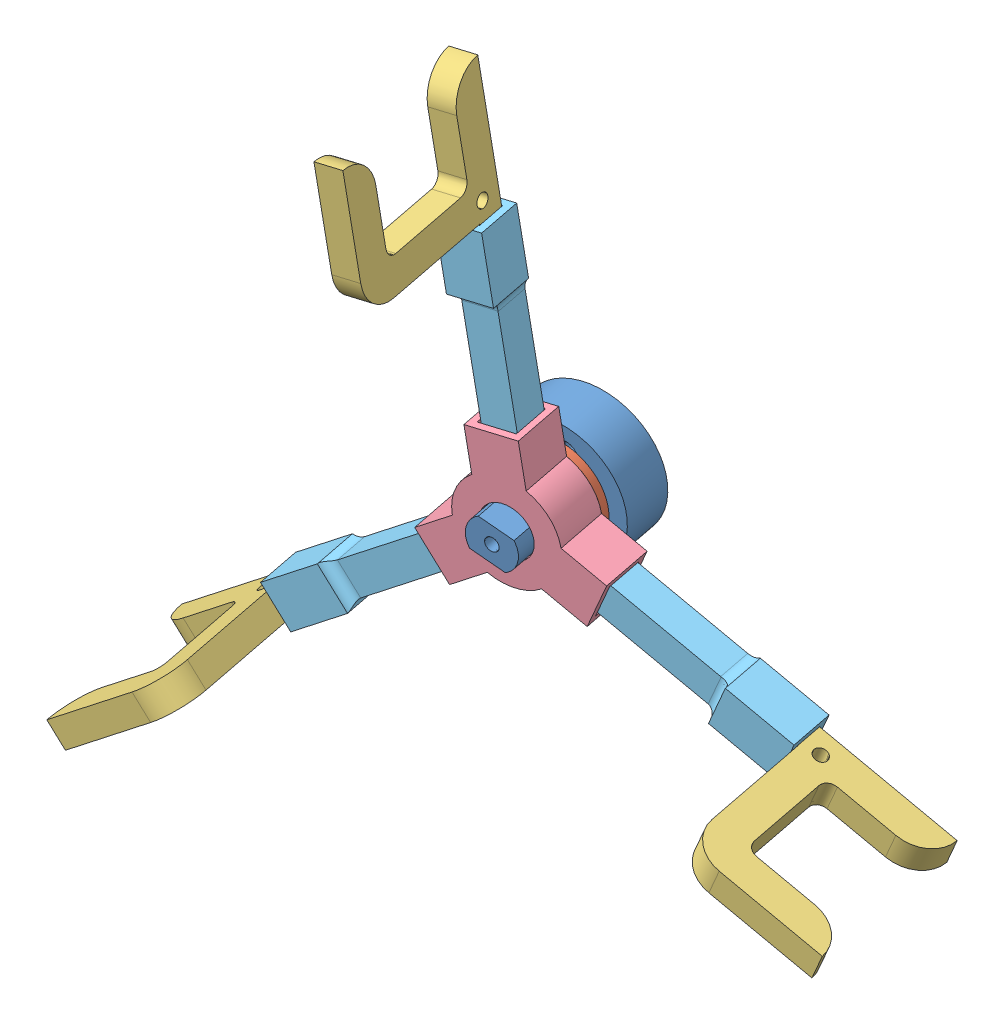
SolidWorks assembly Filament Spool assy, configuration По умолчанию. Lengths in mm.
Overall size (242.81 243.28 106.81).
9 component instances, 5 part files, 25 mates.
Components (placement in the parent):
- spool axes-1: spool axes [По умолчанию] at (2.9579 -0.3616 6.1587) x (0.266619 0.963729 0.011885) z (0.952076 -0.261437 -0.158752) size (40 38 40)
- spool washer 1-1: spool washer 1 [По умолчанию] at (5.5809 -1.3004 23.4355) x (-0.266619 -0.963729 -0.011885) z (0.952076 -0.261437 -0.158752) size (30 2.5 30)
- spool horn-4: spool horn [По умолчанию] at (83.0333 -30.0144 24.6517) x (-0.149887 0.053642 -0.987247) z (-0.392723 -0.919606 0.009658) size (50 60 8)
- spool horn-5: spool horn [По умолчанию] at (-5.4255 77.9644 43.9488) x (-0.149887 0.053642 -0.987247) z (0.982159 0.122779 -0.142443) size (50 60 8)
- spool horn-6: spool horn [По умолчанию] at (-54.4123 -54.1604 44.2071) x (-0.149887 0.053642 -0.987247) z (-0.589436 0.796827 0.132785) size (50 60 8)
- spool hub-2: spool hub [По умолчанию] at (5.5809 -1.3004 23.4355) x (0.982159 0.122779 -0.142443) z (0.149887 -0.053642 0.987247) size (52.98 45.88 15)
- spool needle-4: spool needle [По умолчанию] at (38.7951 -15.5234 19.7472) x (-0.392723 -0.919606 0.009658) z (0.149887 -0.053642 0.987247) size (13.39 70 13.21)
- spool needle-5: spool needle [По умолчанию] at (-22.8857 -23.2341 28.6928) x (-0.589436 0.796827 0.132785) z (0.149887 -0.053642 0.987247) size (13.39 70 13.21)
- spool needle-6: spool needle [По умолчанию] at (1.7778 34.5184 28.0863) x (0.982159 0.122779 -0.142443) z (0.149887 -0.053642 0.987247) size (13.39 70 13.21)
Mates (geometry in assembly coordinates):
- Концентричный2: concentric anti-aligned: cylinder of spool axes-1 through (8.0811 -2.1951 39.9032) axis (-0.149887 0.053642 -0.987247) radius 7.25; cylinder of spool washer 1-1 through (4.6337 -0.9614 17.1965) axis (0.149887 -0.053642 0.987247) radius 7.25
- Совпадение11: coincident anti-aligned: plane of spool axes-1 through (19.0016 0.2501 38.3781) normal (0.266619 0.963729 0.011885); plane of spool washer 1-1 through (6.0335 4.0982 17.2589) normal (-0.266619 -0.963729 -0.011885)
- Совпадение12: coincident aligned: plane of spool needle-5 through (-45.6776 -34.2955 31.5521) normal (-0.149887 0.053642 -0.987247); plane of spool needle-6 through (3.8492 59.9069 29.1512) normal (-0.149887 0.053642 -0.987247)
- Совпадение13: coincident aligned: plane of spool needle-4 through (59.5155 -29.8505 15.8229) normal (-0.149887 0.053642 -0.987247); plane of spool needle-5 through (-45.6776 -34.2955 31.5521) normal (-0.149887 0.053642 -0.987247)
- Совпадение14: coincident anti-aligned: plane of spool hub-2 through (9.9207 10.4068 25.5399) normal (0.149887 -0.053642 0.987247); plane of spool needle-4 through (59.5155 -29.8505 15.8229) normal (-0.149887 0.053642 -0.987247)
- Ширина1: width: plane of spool needle-6 through (11.0267 9.8213 35.4693) normal (0.982159 0.122779 -0.142443); plane of spool needle-6 through (1.2051 8.5935 36.8938) normal (-0.982159 -0.122779 0.142443); plane of spool hub-2 through (0.9322 8.5015 37.7405) normal (0.982159 0.122779 -0.142443); plane of spool hub-2 through (11.5395 9.8275 36.2022) normal (-0.982159 -0.122779 0.142443)
- Ширина2: width: plane of spool needle-5 through (1.405 -12.7091 35.706) normal (0.589436 -0.796827 -0.132785); plane of spool needle-5 through (-4.4893 -4.7408 37.0338) normal (-0.589436 0.796827 0.132785); plane of spool hub-2 through (-4.6052 -4.465 37.8767) normal (0.589436 -0.796827 -0.132785); plane of spool hub-2 through (1.7607 -13.0707 36.4426) normal (-0.589436 0.796827 0.132785)
- Ширина3: width: plane of spool hub-2 through (18.2318 -0.8285 23.6676) normal (-0.392723 -0.919606 0.009658); plane of spool hub-2 through (13.9904 -10.7602 23.7719) normal (0.392723 0.919606 -0.009658); plane of spool needle-4 through (15.6463 -10.9288 33.6405) normal (-0.392723 -0.919606 0.009658); plane of spool needle-4 through (19.5735 -1.7327 33.544) normal (0.392723 0.919606 -0.009658)
- Совпадение15: coincident anti-aligned: plane of spool hub-2 through (19.8505 -1.4078 34.3299) normal (0.90736 -0.389162 -0.158903); plane of spool needle-4 through (19.5735 -1.7327 33.544) normal (-0.90736 0.389162 0.158903)
- Совпадение16: coincident anti-aligned: plane of spool hub-2 through (0.1419 -12.4914 25.7804) normal (-0.793788 -0.601821 0.087815); plane of spool needle-5 through (1.405 -12.7091 35.706) normal (0.793788 0.601821 -0.087815)
- Совпадение17: coincident anti-aligned: plane of spool hub-2 through (-0.6866 9.0808 27.0783) normal (-0.113572 0.990983 0.071087); plane of spool needle-6 through (1.2051 8.5935 36.8938) normal (0.113572 -0.990983 -0.071087)
- Концентричный3: concentric aligned: cylinder of spool axes-1 through (8.0811 -2.1951 39.9032) axis (-0.149887 0.053642 -0.987247) radius 7.25; cylinder of spool hub-2 through (7.8292 -2.105 38.2442) axis (-0.149887 0.053642 -0.987247) radius 7.5
- Совпадение18: coincident anti-aligned: plane of spool horn-4 through (114.6871 -52.4013 8.5004) normal (-0.149887 0.053642 -0.987247); plane of spool needle-6 through (3.4499 59.6941 31.4794) normal (0.149887 -0.053642 0.987247)
- Совпадение19: coincident aligned: plane of spool horn-4 through (114.6871 -52.4013 8.5004) normal (-0.149887 0.053642 -0.987247); plane of spool horn-5 through (-3.61 119.1224 35.7802) normal (-0.149887 0.053642 -0.987247)
- Совпадение20: coincident aligned: plane of spool horn-5 through (-3.61 119.1224 35.7802) normal (-0.149887 0.053642 -0.987247); plane of spool horn-6 through (-92.3782 -71.3223 38.9096) normal (-0.149887 0.053642 -0.987247)
- Ширина4: width: plane of spool horn-4 through (60.2454 -29.0516 18.0346) normal (-0.392723 -0.919606 0.009658); plane of spool horn-4 through (63.3872 -21.6947 17.9573) normal (0.392723 0.919606 -0.009658); plane of spool needle-4 through (64.7594 -21.9208 26.3465) normal (-0.392723 -0.919606 0.009658); plane of spool needle-4 through (61.4213 -29.7374 26.4286) normal (0.392723 0.919606 -0.009658)
- Ширина5: width: plane of spool horn-5 through (3.2043 59.6634 31.515) normal (0.982159 0.122779 -0.142443); plane of spool horn-5 through (-4.6529 58.6811 32.6545) normal (-0.982159 -0.122779 0.142443); plane of spool needle-6 through (4.7239 59.2381 39.871) normal (-0.982159 -0.122779 0.142443); plane of spool needle-6 through (-3.6244 58.1945 41.0817) normal (0.982159 0.122779 -0.142443)
- Ширина6: width: plane of spool horn-6 through (-44.7509 -35.213 33.6406) normal (-0.589436 0.796827 0.132785); plane of spool horn-6 through (-40.0354 -41.5876 32.5784) normal (0.589436 -0.796827 -0.132785); plane of spool needle-5 through (-38.614 -42.2428 40.9368) normal (-0.589436 0.796827 0.132785); plane of spool needle-5 through (-43.6242 -35.4697 42.0654) normal (0.589436 -0.796827 -0.132785)
- Совпадение21: coincident anti-aligned: plane of spool horn-6 through (-43.5518 -35.6421 41.5386) normal (0.793788 0.601821 -0.087815); plane of spool needle-5 through (-39.8881 -41.7868 32.5452) normal (-0.793788 -0.601821 0.087815)
- Совпадение22: coincident anti-aligned: plane of spool horn-5 through (4.4034 59.2342 39.413) normal (0.113572 -0.990983 -0.071087); plane of spool needle-6 through (-4.8985 58.6505 32.6901) normal (-0.113572 0.990983 0.071087)
- Совпадение23: coincident anti-aligned: plane of spool horn-4 through (61.4445 -29.4807 25.9325) normal (-0.90736 0.389162 0.158903); plane of spool needle-4 through (63.4854 -21.4648 17.9549) normal (0.90736 -0.389162 -0.158903)
- Совпадение24: coincident: cylinder of ? through (3.5845 -0.5859 10.2858) axis (0.149887 -0.053642 0.987247) radius 2
- Совпадение25: coincident anti-aligned: plane of spool axes-1 through (5.2062 -1.1663 20.9674) normal (0.149887 -0.053642 0.987247); plane of spool washer 1-1 through (14.0424 30.7731 21.3613) normal (-0.149887 0.053642 -0.987247)
- Совпадение26: coincident anti-aligned: plane of spool washer 1-1 through (14.4171 30.639 23.8294) normal (0.149887 -0.053642 0.987247); plane of spool hub-2 through (13.9945 -56.0395 19.1839) normal (-0.149887 0.053642 -0.987247)
- ПЛОСКОСТЬ1: unknown: moEndPointRef_w of spool hub-2; line of spool hub-2 through (-10.4504 -0.9151 14.399) axis (-0.866025 -0.5 0)
